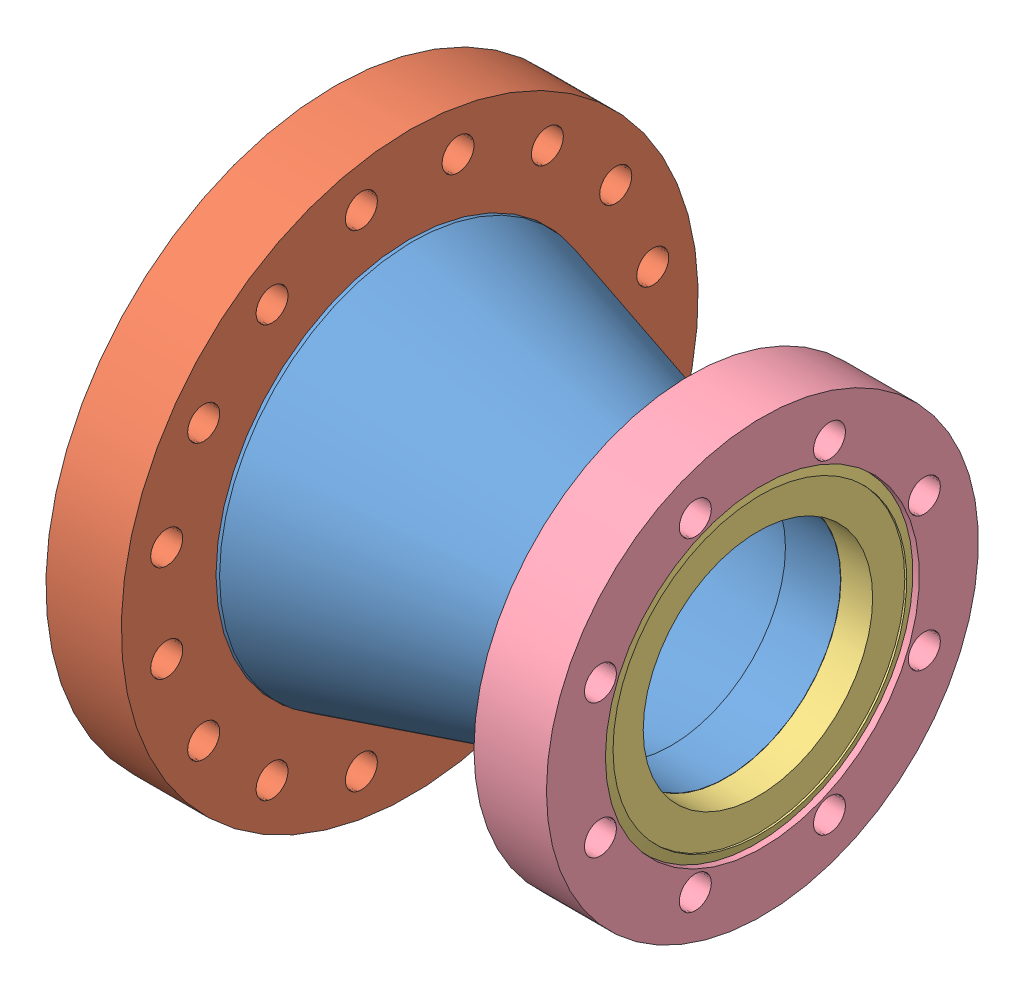
SolidWorks assembly 402038, configuration Default. Lengths in mm.
Overall size (112.51 151.64 151.64).
5 component instances, 4 part files, 0 mates.
Components (placement in the parent):
- 402038-001-1: 402038-001 [Default] at origin size (91.88 101.6 101.6)
- 110026 (6.0 X 4.0 NR)-1: 110026 (6.0 X 4.0 NR) [Default] at (-11.0998 0 0) size (19.81 151.64 151.64)
- 100021 (4.5 X 2.5 R)-1: 100021 (4.5 X 2.5 R) [Default] at (88.7095 0 0) size (19.05 113.54 113.54)
  - 100021 (4.5 X 2.5 INS)-1: 100021 (4.5 X 2.5 INS) [Default] at origin size (12.04 82.3 82.3)
  - 100021 (4.5 X 2.5 REC)-1: 100021 (4.5 X 2.5 REC) [Default] at (-6.35 0 0) x (1 0 0) z (0 0 -1) size (19.05 113.54 113.54)
